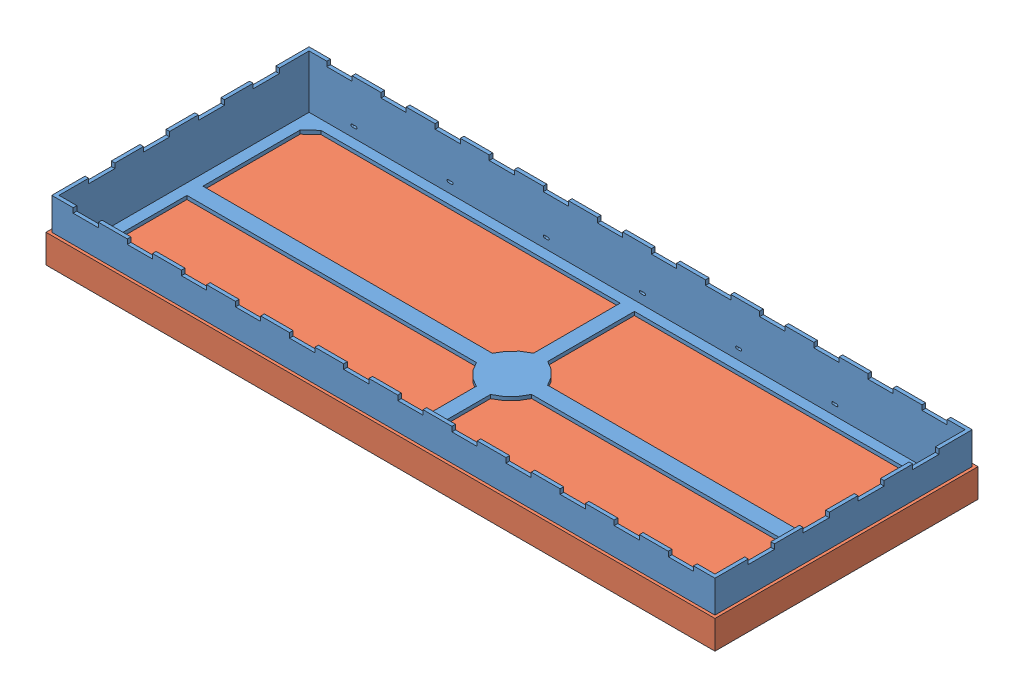
SolidWorks assembly Assem1, configuration Default. Lengths in mm.
Overall size (70.66 6.38 27.79).
2 component instances, 2 part files, 3 mates.
Components (placement in the parent):
- rf frame-1: rf frame [Default] at (33.6242 33.8676 51.6548) size (70.05 5.99 27.18)
- rf cover-1: rf cover [Default] at (33.6242 33.4866 51.6548) size (70.66 3 27.79)
Mates (geometry in assembly coordinates):
- Width1: width: plane of rf cover-1 through (-1.3262 28.3418 37.761) normal (1 0 0); plane of rf cover-1 through (68.5746 28.3418 37.761) normal (-1 0 0); plane of rf frame-1 through (-1.4024 39.862 38.0658) normal (-1 0 0); plane of rf frame-1 through (68.6508 39.862 38.0658) normal (1 0 0)
- Width2: width: plane of rf cover-1 through (-1.7072 28.3418 38.142) normal (0 0 1); plane of rf cover-1 through (-1.7072 28.3418 65.1676) normal (0 0 -1); plane of rf frame-1 through (-1.4024 39.862 38.0658) normal (0 0 -1); plane of rf frame-1 through (-1.4024 39.862 65.2438) normal (0 0 1)
- Coincident1: coincident anti-aligned: plane of rf frame-1 through (33.6242 33.8676 51.6548) normal (0 -1 0); plane of rf cover-1 through (33.6242 33.8676 51.6548) normal (0 1 0)
